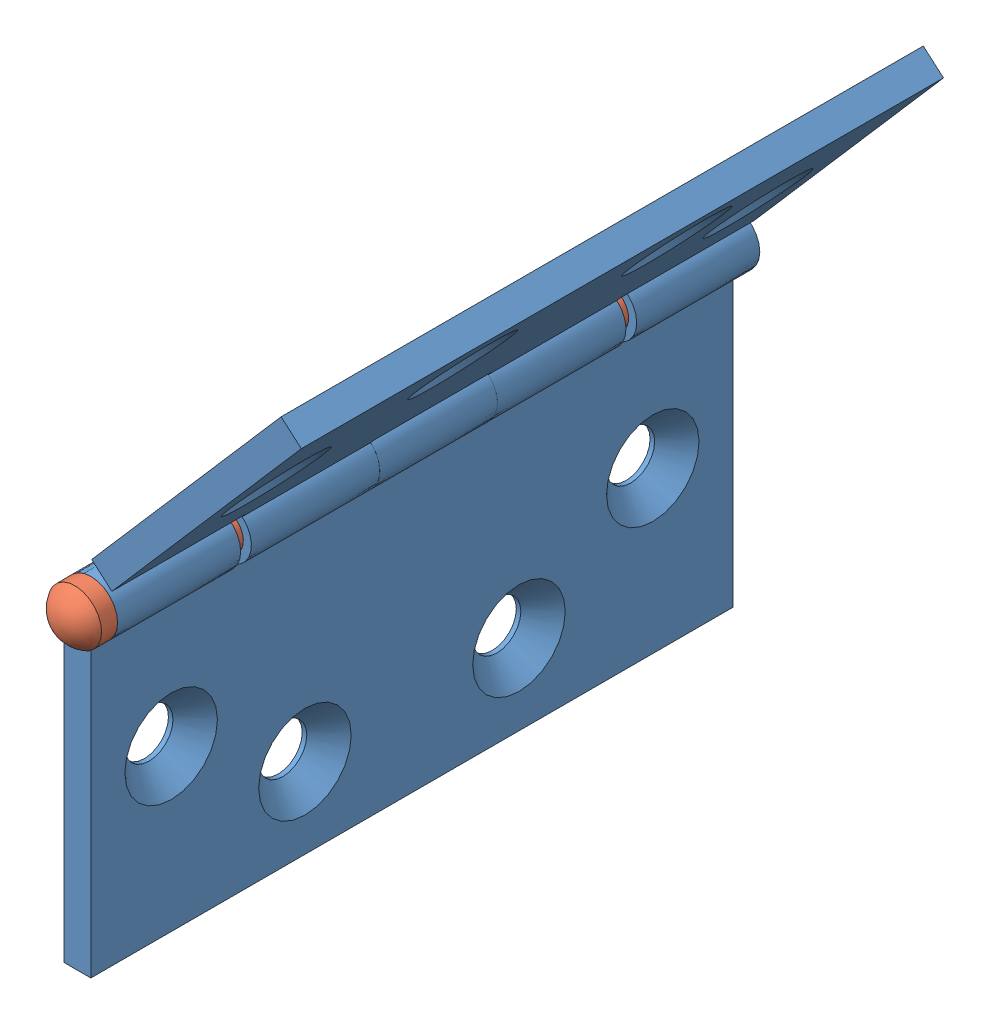
SolidWorks assembly Hinge Assembly, configuration Default. Lengths in mm.
Overall size (50.15 108.59 126).
3 component instances, 2 part files, 6 mates.
Components (placement in the parent):
- Hinge Piece-3: Hinge Piece [InnerCuts] at (35.3838 46.2105 108.2254) size (10 65 120)
- Hinge Piece-4: Hinge Piece [OuterCuts] at (75.9316 154.8043 108.2254) x (0.75528 -0.655403 0) z (0 0 -1) size (10 65 120)
- Pin-1: Pin [Default] at (35.3838 46.2105 168.2254) size (10 10 126)
Mates (geometry in assembly coordinates):
- Coincident1: coincident aligned: plane of Hinge Piece-3 through (35.3838 46.2105 168.2254) normal (0 0 1); plane of Hinge Piece-4 through (75.9316 154.8043 168.2254) normal (0 0 1)
- Concentric1: concentric anti-aligned: cylinder of Hinge Piece-3 through (40.3838 106.2105 168.2254) axis (0 0 -1) radius 5; cylinder of Hinge Piece-4 through (40.3838 106.2105 48.2254) axis (0 0 1) radius 5
- InPlace2: in place: plane of Hinge Piece-3 through (35.3838 46.2105 168.2254) normal (0 0 1); plane of ? through (0 0 168.2254) normal (0 0 1); moOrthogonalPlaneRef_w of Hinge Piece-3 through (35.3838 46.2105 168.2254) normal (0 0 1); plane of ? through (0 0 168.2254) normal (0 1 0); plane of Hinge Piece-3 through (35.3838 46.2105 168.2254) normal (0 0 1); plane of ? through (0 0 168.2254) normal (1 0 0); plane of Hinge Piece-3 through (35.3838 46.2105 168.2254) normal (0 0 1); unknown of Pin-1
- Coincident5: coincident aligned: plane of Hinge Piece-3; plane of Pin-1
- Coincident6: coincident aligned: moOrthogonalPlaneRef_w of Hinge Piece-3 through (35.3838 46.2105 168.2254) normal (0 1 0); plane of Pin-1 through (35.3838 46.2105 168.2254) normal (0 1 0)
- Coincident7: coincident anti-aligned: moOrthogonalPlaneRef_w of Hinge Piece-3 through (35.3838 46.2105 168.2254) normal (-1 0 0); plane of Pin-1 through (35.3838 46.2105 168.2254) normal (1 0 0)
